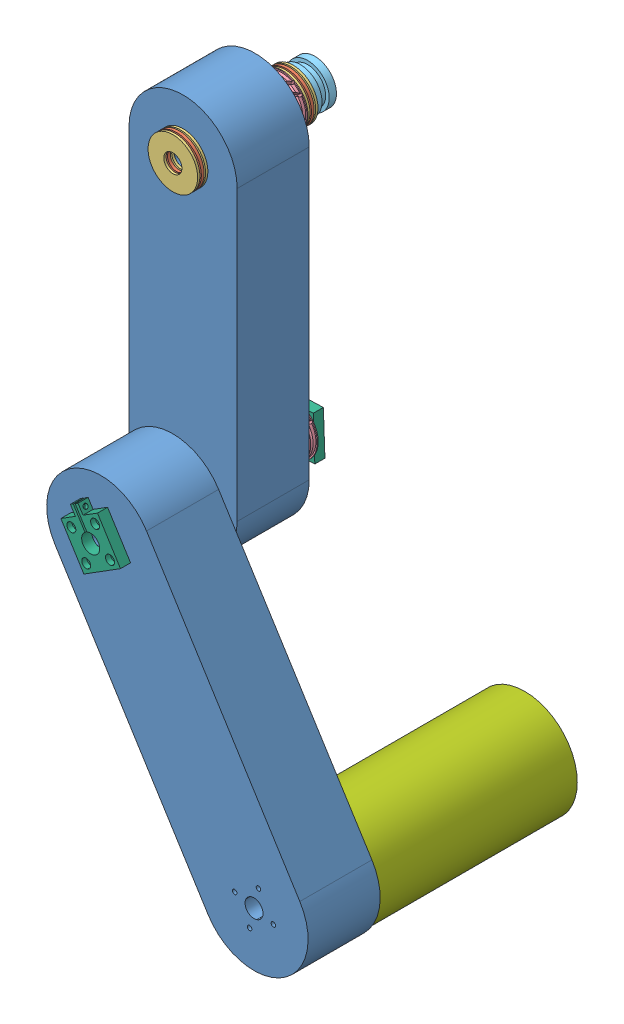
SolidWorks assembly Leg Assembly 2, configuration Default. Lengths in mm.
Overall size (106.54 232.97 98.96).
24 component instances, 7 part files, 22 mates.
Components (placement in the parent):
- Leg Segment-1: Leg Segment [Default] at (40.1502 72.1178 114.0954) size (38.1 139.7 25.4)
- Thrust Bearin-1: Thrust Bearin [Default] at (47.0734 110.7093 151.849) x (0.547792 0.836615 0) z (-0.836615 0.547792 0) size (24.23 3.61 24.23)
  - 5909K23_Needle-Roller Thrust Bearing-1: 5909K23_Needle-Roller Thrust Bearing [5909K23] at (6.4213 10.5486 12.4797) size (17.46 1.98 17.46)
  - 5909K231_0.032 Thick Washer for 1-4 Shaft Diameter Needle-Roller Thrust Bearing-1: 5909K231_0.032 Thick Washer for 1-4 Shaft Diameter Needle-Roller Thrust Bearing [5909K231] at (6.4213 11.9472 12.4797) x (-0.830038 0 -0.557707) z (0 -1 0) size (17.46 17.46 0.81)
  - 5909K231_0.032 Thick Washer for 1-4 Shaft Diameter Needle-Roller Thrust Bearing-2: 5909K231_0.032 Thick Washer for 1-4 Shaft Diameter Needle-Roller Thrust Bearing [5909K231] at (6.4213 9.15 12.4797) x (0.995065 0 0.099222) z (0 1 0) size (17.46 17.46 0.81)
- SDP_sdpsi_a_6p_9-0801508.stp-1: SDP_sdpsi_a_6p_9-0801508.stp [Default] at (40.1502 122.9178 106.3563) size (18.19 18.19 9.53)
- Thrust Bearin-2: Thrust Bearin [Default] at (33.7289 135.3975 91.9492) x (1 0 0) z (0 -1 0) size (24.23 3.61 24.23)
  - 5909K23_Needle-Roller Thrust Bearing-1: 5909K23_Needle-Roller Thrust Bearing [5909K23] at (6.4213 10.5486 12.4797) size (17.46 1.98 17.46)
  - 5909K231_0.032 Thick Washer for 1-4 Shaft Diameter Needle-Roller Thrust Bearing-1: 5909K231_0.032 Thick Washer for 1-4 Shaft Diameter Needle-Roller Thrust Bearing [5909K231] at (6.4213 11.9472 12.4797) x (-0.830038 0 -0.557707) z (0 -1 0) size (17.46 17.46 0.81)
  - 5909K231_0.032 Thick Washer for 1-4 Shaft Diameter Needle-Roller Thrust Bearing-2: 5909K231_0.032 Thick Washer for 1-4 Shaft Diameter Needle-Roller Thrust Bearing [5909K231] at (6.4213 9.15 12.4797) x (0.995065 0 0.099222) z (0 1 0) size (17.46 17.46 0.81)
- guide pulley-1: guide pulley [Default] at (40.1502 122.9178 93.0728) size (15.24 15.24 7.62)
- Leg Segment-2: Leg Segment [Default] at (67.1566 -21.709 143.1054) x (0.846983 0.531621 0) z (0 0 1) size (38.1 139.7 25.4)
- Thrust Bearin-3: Thrust Bearin [Default] at (33.7289 8.838 151.849) x (1 0 0) z (0 1 0) size (24.23 3.61 24.23)
  - 5909K23_Needle-Roller Thrust Bearing-1: 5909K23_Needle-Roller Thrust Bearing [5909K23] at (6.4213 10.5486 12.4797) size (17.46 1.98 17.46)
  - 5909K231_0.032 Thick Washer for 1-4 Shaft Diameter Needle-Roller Thrust Bearing-1: 5909K231_0.032 Thick Washer for 1-4 Shaft Diameter Needle-Roller Thrust Bearing [5909K231] at (6.4213 11.9472 12.4797) x (-0.830038 0 -0.557707) z (0 -1 0) size (17.46 17.46 0.81)
  - 5909K231_0.032 Thick Washer for 1-4 Shaft Diameter Needle-Roller Thrust Bearing-2: 5909K231_0.032 Thick Washer for 1-4 Shaft Diameter Needle-Roller Thrust Bearing [5909K231] at (6.4213 9.15 12.4797) x (0.995065 0 0.099222) z (0 1 0) size (17.46 17.46 0.81)
- Square Clamp-2: Square Clamp [Default] at (40.1502 21.3178 168.5054) x (0.846983 0.531621 0) z (0.531621 -0.846983 0) size (15.24 3.56 18.54)
- Thrust Bearin-4: Thrust Bearin [Default] at (33.7289 33.7975 101.7418) x (1 0 0) z (0 -1 0) size (24.23 3.61 24.23)
  - 5909K23_Needle-Roller Thrust Bearing-1: 5909K23_Needle-Roller Thrust Bearing [5909K23] at (6.4213 10.5486 12.4797) size (17.46 1.98 17.46)
  - 5909K231_0.032 Thick Washer for 1-4 Shaft Diameter Needle-Roller Thrust Bearing-1: 5909K231_0.032 Thick Washer for 1-4 Shaft Diameter Needle-Roller Thrust Bearing [5909K231] at (6.4213 11.9472 12.4797) x (-0.830038 0 -0.557707) z (0 -1 0) size (17.46 17.46 0.81)
  - 5909K231_0.032 Thick Washer for 1-4 Shaft Diameter Needle-Roller Thrust Bearing-2: 5909K231_0.032 Thick Washer for 1-4 Shaft Diameter Needle-Roller Thrust Bearing [5909K231] at (6.4213 9.15 12.4797) x (0.995065 0 0.099222) z (0 1 0) size (17.46 17.46 0.81)
- SDP_sdpsi_a_6p_9-0801508.stp-2: SDP_sdpsi_a_6p_9-0801508.stp [Default] at (40.1502 21.3178 102.7464) size (18.19 18.19 9.53)
- Square Clamp-3: Square Clamp [Default] at (40.1502 21.3178 100.9604) x (-0.999351 -0.03601 0) z (0.03601 -0.999351 0) size (15.24 3.56 18.54)
- Lowresmotor-1: Lowresmotor [Default] at (94.1629 -64.7357 143.1054) x (-1 0 0) z (0 0 -1) size (37 37 92.1)
Mates (geometry in assembly coordinates):
- Coincident1: coincident: plane of Leg Segment-1 through (40.1502 21.3178 139.4954) normal (0 0 1); plane of Thrust Bearin-1/5909K231_0.032 Thick Washer for 1-4 Shaft Diameter Needle-Roller Thrust Bearing-1 through (40.1502 122.9178 139.4954) normal (0 0 -1)
- Concentric1: concentric: circle of Leg Segment-1; circle of Thrust Bearin-1/5909K231_0.032 Thick Washer for 1-4 Shaft Diameter Needle-Roller Thrust Bearing-2
- Concentric12: concentric: circle of Leg Segment-1; circle of SDP_sdpsi_a_6p_9-0801508.stp-1
- Coincident14: coincident: plane of Leg Segment-1 through (40.1502 21.3178 114.0954) normal (0 0 -1); plane of SDP_sdpsi_a_6p_9-0801508.stp-1 through (40.1502 122.9178 114.0954) normal (0 0 1)
- Concentric13: concentric: circle of SDP_sdpsi_a_6p_9-0801508.stp-1; circle of Thrust Bearin-2/5909K231_0.032 Thick Washer for 1-4 Shaft Diameter Needle-Roller Thrust Bearing-1
- Concentric14: concentric: circle of Thrust Bearin-2/5909K231_0.032 Thick Washer for 1-4 Shaft Diameter Needle-Roller Thrust Bearing-2; circle of guide pulley-1
- Coincident15: coincident: plane of Thrust Bearin-2/5909K231_0.032 Thick Washer for 1-4 Shaft Diameter Needle-Roller Thrust Bearing-2 through (40.1502 122.9178 100.6928) normal (0 0 -1); plane of guide pulley-1 through (40.1502 122.9178 100.6928) normal (0 0 1)
- Coincident16: coincident: plane of Leg Segment-1 through (40.1502 21.3178 139.4954) normal (0 0 1); plane of Thrust Bearin-3/5909K231_0.032 Thick Washer for 1-4 Shaft Diameter Needle-Roller Thrust Bearing-1 through (40.1502 21.3178 139.4954) normal (0 0 -1)
- Concentric16: concentric: circle of Leg Segment-1; circle of Thrust Bearin-3/5909K231_0.032 Thick Washer for 1-4 Shaft Diameter Needle-Roller Thrust Bearing-2
- Concentric17: concentric: circle of Leg Segment-2; circle of Thrust Bearin-3/5909K231_0.032 Thick Washer for 1-4 Shaft Diameter Needle-Roller Thrust Bearing-2
- Coincident19: coincident: plane of Leg Segment-2 through (94.1629 -64.7357 143.1054) normal (0 0 -1); plane of Thrust Bearin-3/5909K231_0.032 Thick Washer for 1-4 Shaft Diameter Needle-Roller Thrust Bearing-2 through (40.1502 21.3178 143.1054) normal (0 0 1)
- Coincident21: coincident: plane of Leg Segment-2 through (94.1629 -64.7357 168.5054) normal (0 0 1); plane of Square Clamp-2 through (40.1502 21.3178 168.5054) normal (0 0 -1)
- Concentric18: concentric: circle of Leg Segment-2; circle of Square Clamp-2
- Concentric19: concentric: circle of Leg Segment-2; circle of Square Clamp-2
- Concentric20: concentric: circle of Leg Segment-1; circle of Thrust Bearin-4/5909K231_0.032 Thick Washer for 1-4 Shaft Diameter Needle-Roller Thrust Bearing-1
- Coincident24: coincident: plane of Leg Segment-1 through (40.1502 21.3178 114.0954) normal (0 0 -1); plane of Thrust Bearin-4/5909K231_0.032 Thick Washer for 1-4 Shaft Diameter Needle-Roller Thrust Bearing-1 through (40.1502 21.3178 114.0954) normal (0 0 1)
- Concentric21: concentric: circle of Thrust Bearin-4/5909K231_0.032 Thick Washer for 1-4 Shaft Diameter Needle-Roller Thrust Bearing-2; circle of SDP_sdpsi_a_6p_9-0801508.stp-2
- Coincident25: coincident: plane of Thrust Bearin-4/5909K231_0.032 Thick Washer for 1-4 Shaft Diameter Needle-Roller Thrust Bearing-2 through (40.1502 21.3178 110.4854) normal (0 0 -1); plane of SDP_sdpsi_a_6p_9-0801508.stp-2 through (40.1502 21.3178 110.4854) normal (0 0 1)
- Concentric22: concentric: circle of SDP_sdpsi_a_6p_9-0801508.stp-2; circle of Square Clamp-3
- Coincident26: coincident: plane of SDP_sdpsi_a_6p_9-0801508.stp-2 through (40.1502 21.3178 100.9604) normal (0 0 -1); plane of Square Clamp-3 through (40.1502 21.3178 100.9604) normal (0 0 1)
- Coincident27: coincident: plane of Leg Segment-2 through (94.1629 -64.7357 143.1054) normal (0 0 -1); plane of Lowresmotor-1 through (94.1629 -64.7357 143.1054) normal (0 0 1)
- Concentric23: concentric: circle of Leg Segment-2; circle of Lowresmotor-1
